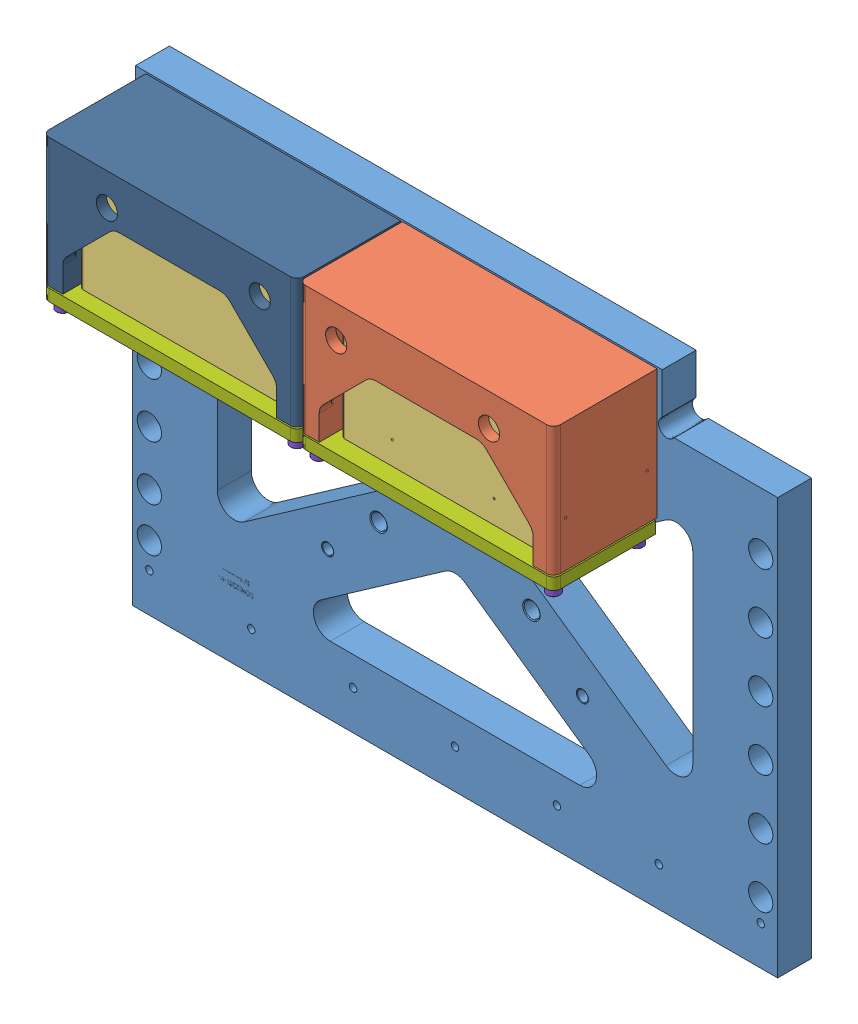
SolidWorks assembly D1001760 - Stage 1 Vibration Absorber (door), configuration Default. Lengths in mm.
Overall size (482.6 350.77 103.82).
71 component instances, 11 part files, 155 mates.
Components (placement in the parent):
- D0902281 Door, Stage 1, BSC ISI-1: D0902281 Door, Stage 1, BSC ISI [1-Inch Stretch] at origin size (482.6 350.77 25.4)
- D1001759 - Left clamp for Stage 1 Vibration Absorber-1: D1001759 - Left clamp for Stage 1 Vibration Absorber [Default] at (55.88 125.857 25.4) x (-1 0 0) z (0 1 0) size (190.5 77.47 96.52)
- D1001758 - Mass for Stage 1 Vibration Absorber-1: D1001758 - Mass for Stage 1 Vibration Absorber [Default] at (57.15 120.2373 35.56) x (1 0 0) z (0 -1 0) size (152.4 55.88 84.61)
- D1000939 Viton for SEI vibration absorbers with 10% strain-9: D1000939 Viton for SEI vibration absorbers with 10% strain [Default] at (126.492 162.5409 42.418) size (3.56 1.42 3.56)
- D1000939 Viton for SEI vibration absorbers with 10% strain-10: D1000939 Viton for SEI vibration absorbers with 10% strain [Default] at (-14.732 162.5409 42.418) size (3.56 1.42 3.56)
- D1000939 Viton for SEI vibration absorbers with 10% strain-11: D1000939 Viton for SEI vibration absorbers with 10% strain [Default] at (126.492 162.5409 85.852) size (3.56 1.42 3.56)
- D1000939 Viton for SEI vibration absorbers with 10% strain-12: D1000939 Viton for SEI vibration absorbers with 10% strain [Default] at (-14.732 162.5409 85.852) size (3.56 1.42 3.56)
- D1000939 Viton for SEI vibration absorbers with 10% strain-13: D1000939 Viton for SEI vibration absorbers with 10% strain [Default] at (126.492 76.5175 42.418) size (3.56 1.42 3.56)
- D1000939 Viton for SEI vibration absorbers with 10% strain-14: D1000939 Viton for SEI vibration absorbers with 10% strain [Default] at (-14.732 76.5175 42.418) size (3.56 1.42 3.56)
- D1000939 Viton for SEI vibration absorbers with 10% strain-15: D1000939 Viton for SEI vibration absorbers with 10% strain [Default] at (-14.732 76.5175 85.852) size (3.56 1.42 3.56)
- D1000939 Viton for SEI vibration absorbers with 10% strain-16: D1000939 Viton for SEI vibration absorbers with 10% strain [Default] at (126.492 76.5175 85.852) size (3.56 1.42 3.56)
- MC MASTER_93574A513-1: MC MASTER_93574A513 [Default] at (143.51 77.089 95.25) size (9.47 0.51 9.47)
- MC MASTER_93574A513-2: MC MASTER_93574A513 [Default] at (143.51 76.581 95.25) size (9.47 0.51 9.47)
- MC MASTER_93574A505-1: MC MASTER_93574A505 [Default] at (143.51 76.5048 95.25) x (0.999977 0 0.00673) z (0 1 0) size (9.47 9.47 0.08)
- D1001757 - Top clamp for Stage 1 Vibration Absorber-1: D1001757 - Top clamp for Stage 1 Vibration Absorber [Default] at (55.88 67.6148 64.77) size (190.5 8.89 76.2)
- MC MASTER_93574A513-3: MC MASTER_93574A513 [Default] at (-31.75 77.089 95.25) x (0.993606 0 -0.112902) z (0.112902 0 0.993606) size (9.47 0.51 9.47)
- MC MASTER_93574A513-4: MC MASTER_93574A513 [Default] at (-31.75 76.581 95.25) size (9.47 0.51 9.47)
- MC MASTER_93574A505-2: MC MASTER_93574A505 [Default] at (-31.75 76.5048 95.25) x (1 0 0) z (0 1 0) size (9.47 9.47 0.08)
- MC MASTER_93574A513-5: MC MASTER_93574A513 [Default] at (-31.75 77.089 33.02) size (9.47 0.51 9.47)
- MC MASTER_93574A513-6: MC MASTER_93574A513 [Default] at (-31.75 76.581 33.02) size (9.47 0.51 9.47)
- MC MASTER_93574A505-3: MC MASTER_93574A505 [Default] at (-31.75 76.5048 33.02) x (0.59125 0 -0.806489) z (0 1 0) size (9.47 9.47 0.08)
- MC MASTER_93574A513-7: MC MASTER_93574A513 [Default] at (143.51 77.089 33.02) x (0.880275 0 -0.474465) z (0.474465 0 0.880275) size (9.47 0.51 9.47)
- MC MASTER_93574A513-8: MC MASTER_93574A513 [Default] at (143.51 76.581 33.02) x (0.988184 0 -0.153269) z (0.153269 0 0.988184) size (9.47 0.51 9.47)
- MC MASTER_93574A505-4: MC MASTER_93574A505 [Default] at (143.51 76.5048 33.02) x (0.954256 0 -0.298991) z (0 1 0) size (9.47 9.47 0.08)
- HOLOKROME_78062-1: HOLOKROME_78062 [.250-20 x 1.0L] at (143.51 67.1068 95.25) x (-0.982351 0 0.187046) z (0.187046 0 0.982351) size (9.53 31.75 9.53)
- MC MASTER 96861A600-1: MC MASTER 96861A600 [96861A600] at (143.51 67.3608 95.25) x (0.307511 0 0.951544) z (0 1 0) size (11.94 11.94 0.52)
- HOLOKROME_78062-3: HOLOKROME_78062 [.250-20 x 1.0L] at (143.51 67.1068 33.02) x (-0.709304 0 0.704903) z (0.704903 0 0.709304) size (9.53 31.75 9.53)
- HOLOKROME_78062-5: HOLOKROME_78062 [.250-20 x 1.0L] at (-31.75 67.1068 33.02) x (0.117481 0 0.993075) z (0.993075 0 -0.117481) size (9.53 31.75 9.53)
- HOLOKROME_78062-4: HOLOKROME_78062 [.250-20 x 1.0L] at (-31.75 67.1068 95.25) x (-0.122585 0 0.992458) z (0.992458 0 0.122585) size (9.53 31.75 9.53)
- D1001764 Right clamp for Stage 1 Vibration Absorber-1: D1001764 Right clamp for Stage 1 Vibration Absorber [Default] at (-135.89 125.857 25.4) x (-1 0 0) z (0 1 0) size (190.5 77.47 96.52)
- D1001758 - Mass for Stage 1 Vibration Absorber-2: D1001758 - Mass for Stage 1 Vibration Absorber [Default] at (-137.3357 120.2373 92.71) x (-1 0 0) z (0 -1 0) size (152.4 55.88 84.61)
- D1000939 Viton for SEI vibration absorbers with 10% strain-17: D1000939 Viton for SEI vibration absorbers with 10% strain [Default] at (-65.278 163.957 42.418) x (-1 0 0) z (0 0 1) size (3.56 1.42 3.56)
- D1000939 Viton for SEI vibration absorbers with 10% strain-18: D1000939 Viton for SEI vibration absorbers with 10% strain [Default] at (-206.502 162.5409 42.418) size (3.56 1.42 3.56)
- D1000939 Viton for SEI vibration absorbers with 10% strain-19: D1000939 Viton for SEI vibration absorbers with 10% strain [Default] at (-206.502 162.5409 89.408) x (-1 0 0) z (0 0 -1) size (3.56 1.42 3.56)
- D1000939 Viton for SEI vibration absorbers with 10% strain-20: D1000939 Viton for SEI vibration absorbers with 10% strain [Default] at (-65.278 162.5409 85.852) size (3.56 1.42 3.56)
- D1000939 Viton for SEI vibration absorbers with 10% strain-21: D1000939 Viton for SEI vibration absorbers with 10% strain [Default] at (-65.278 76.5175 85.852) size (3.56 1.42 3.56)
- D1000939 Viton for SEI vibration absorbers with 10% strain-22: D1000939 Viton for SEI vibration absorbers with 10% strain [Default] at (-65.278 76.5175 42.418) size (3.56 1.42 3.56)
- D1000939 Viton for SEI vibration absorbers with 10% strain-23: D1000939 Viton for SEI vibration absorbers with 10% strain [Default] at (-206.502 76.5175 42.418) size (3.56 1.42 3.56)
- D1000939 Viton for SEI vibration absorbers with 10% strain-24: D1000939 Viton for SEI vibration absorbers with 10% strain [Default] at (-206.502 76.5175 85.852) size (3.56 1.42 3.56)
- D1001757 - Top clamp for Stage 1 Vibration Absorber-2: D1001757 - Top clamp for Stage 1 Vibration Absorber [Default] at (-135.89 67.6148 64.77) size (190.5 8.89 76.2)
- MC MASTER_93574A513-9: MC MASTER_93574A513 [Default] at (-48.26 77.089 95.25) size (9.47 0.51 9.47)
- MC MASTER_93574A513-10: MC MASTER_93574A513 [Default] at (-48.26 76.581 95.25) size (9.47 0.51 9.47)
- MC MASTER_93574A505-5: MC MASTER_93574A505 [Default] at (-48.26 76.5048 95.25) x (1 0 0) z (0 1 0) size (9.47 9.47 0.08)
- MC MASTER_93574A513-11: MC MASTER_93574A513 [Default] at (-48.26 77.089 33.02) size (9.47 0.51 9.47)
- MC MASTER_93574A513-12: MC MASTER_93574A513 [Default] at (-48.26 76.581 33.02) size (9.47 0.51 9.47)
- MC MASTER_93574A505-6: MC MASTER_93574A505 [Default] at (-48.26 76.5048 33.02) x (1 0 0) z (0 1 0) size (9.47 9.47 0.08)
- MC MASTER_93574A513-13: MC MASTER_93574A513 [Default] at (-223.52 77.089 33.02) size (9.47 0.51 9.47)
- MC MASTER_93574A513-14: MC MASTER_93574A513 [Default] at (-223.52 76.581 33.02) size (9.47 0.51 9.47)
- MC MASTER_93574A505-7: MC MASTER_93574A505 [Default] at (-223.52 76.5048 33.02) x (1 0 0) z (0 1 0) size (9.47 9.47 0.08)
- MC MASTER_93574A513-15: MC MASTER_93574A513 [Default] at (-223.52 77.089 95.25) size (9.47 0.51 9.47)
- MC MASTER_93574A513-16: MC MASTER_93574A513 [Default] at (-223.52 76.581 95.25) size (9.47 0.51 9.47)
- MC MASTER_93574A505-8: MC MASTER_93574A505 [Default] at (-223.52 76.5048 95.25) x (1 0 0) z (0 1 0) size (9.47 9.47 0.08)
- MC MASTER 96861A600-5: MC MASTER 96861A600 [96861A600] at (-48.26 67.3608 95.25) x (1 0 0) z (0 1 0) size (11.94 11.94 0.52)
- HOLOKROME_78062-6: HOLOKROME_78062 [.250-20 x 1.0L] at (-48.26 67.1068 95.25) x (0.448283 0 -0.893892) z (-0.893892 0 -0.448283) size (9.53 31.75 9.53)
- HOLOKROME_78062-9: HOLOKROME_78062 [.250-20 x 1.0L] at (-223.52 67.1068 95.25) x (-0.362071 0 -0.93215) z (-0.93215 0 0.362071) size (9.53 31.75 9.53)
- HOLOKROME_78062-10: HOLOKROME_78062 [.250-20 x 1.0L] at (-223.52 67.1068 33.02) x (0.443089 0 -0.896478) z (-0.896478 0 -0.443089) size (9.53 31.75 9.53)
- HOLOKROME_78062-8: HOLOKROME_78062 [.250-20 x 1.0L] at (-48.26 67.1068 33.02) x (0.795854 0 -0.605488) z (-0.605488 0 -0.795854) size (9.53 31.75 9.53)
- MSC 48632822-1: MSC 48632822 [93615A520] at (102.87 97.917 2.54) x (-0.923728 -0.383049 0) z (0 0 -1) size (14.27 14.27 31.94)
- MSC 48632822-5: MSC 48632822 [93615A520] at (-11.43 97.917 2.54) x (-0.923728 -0.383049 0) z (0 0 -1) size (14.27 14.27 31.94)
- MSC 48632822-6: MSC 48632822 [93615A520] at (102.87 149.987 2.54) x (-0.923728 -0.383049 0) z (0 0 -1) size (14.27 14.27 31.94)
- MSC 48632822-7: MSC 48632822 [93615A520] at (-11.43 149.987 2.54) x (-0.923728 -0.383049 0) z (0 0 -1) size (14.27 14.27 31.94)
- MSC 48632822-8: MSC 48632822 [93615A520] at (-182.88 97.917 2.54) x (-0.923728 -0.383049 0) z (0 0 -1) size (14.27 14.27 31.94)
- MSC 48632822-10: MSC 48632822 [93615A520] at (-182.88 149.987 2.54) x (-0.923728 -0.383049 0) z (0 0 -1) size (14.27 14.27 31.94)
- MSC 48632822-11: MSC 48632822 [93615A520] at (-68.58 97.917 2.54) x (-0.923728 -0.383049 0) z (0 0 -1) size (14.27 14.27 31.94)
- MSC 48632822-12: MSC 48632822 [93615A520] at (-68.58 149.987 2.54) x (-0.923728 -0.383049 0) z (0 0 -1) size (14.27 14.27 31.94)
- MC MASTER 96861A600-2: MC MASTER 96861A600 [96861A600] at (-31.6876 67.3608 95.4288) x (-0.833011 0 -0.553256) z (0 1 0) size (11.94 11.94 0.52)
- MC MASTER 96861A600-3: MC MASTER 96861A600 [96861A600] at (-31.4805 67.3608 33.4836) x (-0.299196 0 -0.954192) z (0 1 0) size (11.94 11.94 0.52)
- MC MASTER 96861A600-4: MC MASTER 96861A600 [96861A600] at (143.1765 67.3608 33.3053) x (0.837808 0 0.545966) z (0 1 0) size (11.94 11.94 0.52)
- MC MASTER 96861A600-6: MC MASTER 96861A600 [96861A600] at (-223.4576 67.3608 95.4288) x (-0.782608 0 0.622515) z (0 1 0) size (11.94 11.94 0.52)
- MC MASTER 96861A600-7: MC MASTER 96861A600 [96861A600] at (-223.2505 67.3608 33.4836) x (-0.999962 0 -0.008727) z (0 1 0) size (11.94 11.94 0.52)
- MC MASTER 96861A600-8: MC MASTER 96861A600 [96861A600] at (-48.5935 67.3608 33.3053) x (0.777146 0 -0.62932) z (0 1 0) size (11.94 11.94 0.52)
Mates (geometry in assembly coordinates):
- Coincident1: coincident anti-aligned: plane of D0902281 Door, Stage 1, BSC ISI-1 through (-241.3 -175.387 25.4) normal (0 0 1); plane of D1001759 - Left clamp for Stage 1 Vibration Absorber-1 through (151.13 77.597 25.4) normal (0 0 -1)
- Concentric2: concentric aligned: cylinder of D0902281 Door, Stage 1, BSC ISI-1 through (-11.43 97.917 25.4) axis (0 0 1) radius 5.8445; cylinder of D1001759 - Left clamp for Stage 1 Vibration Absorber-1 through (-11.43 97.917 33.02) axis (0 0 1) radius 5.1587
- Concentric3: concentric aligned: cylinder of D0902281 Door, Stage 1, BSC ISI-1 through (102.87 149.987 25.4) axis (0 0 1) radius 5.8445; cylinder of D1001759 - Left clamp for Stage 1 Vibration Absorber-1 through (102.87 149.987 33.02) axis (0 0 1) radius 5.1587
- Distance2: distance = 2.54 mm anti-aligned: plane of D1001758 - Mass for Stage 1 Vibration Absorber-1 through (-19.05 162.5409 35.56) normal (0 0 -1); plane of D1001759 - Left clamp for Stage 1 Vibration Absorber-1 through (-24.13 163.957 33.02) normal (0 0 1)
- Distance11: distance = 2.54 mm anti-aligned: plane of D1001758 - Mass for Stage 1 Vibration Absorber-1 through (133.35 77.9336 91.44) normal (1 0 0); plane of D1001759 - Left clamp for Stage 1 Vibration Absorber-1 through (135.89 163.957 95.25) normal (-1 0 0)
- Coincident50: coincident anti-aligned: plane of D1001759 - Left clamp for Stage 1 Vibration Absorber-1 through (135.89 163.957 33.02) normal (0 -1 0); plane of D1000939 Viton for SEI vibration absorbers with 10% strain-9 through (128.27 163.957 40.64) normal (0 1 0)
- Distance20: distance = 7.62 mm anti-aligned: plane of D1000939 Viton for SEI vibration absorbers with 10% strain-9 through (124.714 163.957 40.64) normal (0 0 -1); plane of D1001759 - Left clamp for Stage 1 Vibration Absorber-1 through (-24.13 163.957 33.02) normal (0 0 1)
- Distance21: distance = 7.62 mm anti-aligned: plane of D1000939 Viton for SEI vibration absorbers with 10% strain-9 through (128.27 163.957 44.196) normal (1 0 0); plane of D1001759 - Left clamp for Stage 1 Vibration Absorber-1 through (135.89 163.957 95.25) normal (-1 0 0)
- Coincident53: coincident anti-aligned: plane of D1001759 - Left clamp for Stage 1 Vibration Absorber-1 through (135.89 163.957 33.02) normal (0 -1 0); plane of D1000939 Viton for SEI vibration absorbers with 10% strain-10 through (-12.954 163.957 40.64) normal (0 1 0)
- Distance22: distance = 7.62 mm anti-aligned: plane of D1000939 Viton for SEI vibration absorbers with 10% strain-10 through (-16.51 163.957 44.196) normal (-1 0 0); plane of D1001759 - Left clamp for Stage 1 Vibration Absorber-1 through (-24.13 163.957 95.25) normal (1 0 0)
- Distance23: distance = 7.62 mm anti-aligned: plane of D1000939 Viton for SEI vibration absorbers with 10% strain-10 through (-16.51 163.957 40.64) normal (0 0 -1); plane of D1001759 - Left clamp for Stage 1 Vibration Absorber-1 through (-24.13 163.957 33.02) normal (0 0 1)
- Coincident56: coincident anti-aligned: plane of D1001759 - Left clamp for Stage 1 Vibration Absorber-1 through (135.89 163.957 33.02) normal (0 -1 0); plane of D1000939 Viton for SEI vibration absorbers with 10% strain-11 through (128.27 163.957 84.074) normal (0 1 0)
- Distance24: distance = 7.62 mm anti-aligned: plane of D1000939 Viton for SEI vibration absorbers with 10% strain-11 through (128.27 163.957 87.63) normal (1 0 0); plane of D1001759 - Left clamp for Stage 1 Vibration Absorber-1 through (135.89 163.957 95.25) normal (-1 0 0)
- Distance25: distance = 7.62 mm anti-aligned: plane of D1000939 Viton for SEI vibration absorbers with 10% strain-11 through (124.714 163.957 87.63) normal (0 0 1); plane of D1001759 - Left clamp for Stage 1 Vibration Absorber-1 through (135.89 163.957 95.25) normal (0 0 -1)
- Coincident59: coincident anti-aligned: plane of D1001759 - Left clamp for Stage 1 Vibration Absorber-1 through (135.89 163.957 33.02) normal (0 -1 0); plane of D1000939 Viton for SEI vibration absorbers with 10% strain-12 through (-12.954 163.957 84.074) normal (0 1 0)
- Distance26: distance = 7.62 mm anti-aligned: plane of D1000939 Viton for SEI vibration absorbers with 10% strain-12 through (-16.51 163.957 87.63) normal (-1 0 0); plane of D1001759 - Left clamp for Stage 1 Vibration Absorber-1 through (-24.13 163.957 95.25) normal (1 0 0)
- Distance27: distance = 7.62 mm anti-aligned: plane of D1000939 Viton for SEI vibration absorbers with 10% strain-12 through (-16.51 163.957 87.63) normal (0 0 1); plane of D1001759 - Left clamp for Stage 1 Vibration Absorber-1 through (135.89 163.957 95.25) normal (0 0 -1)
- Coincident62: coincident anti-aligned: plane of D1001758 - Mass for Stage 1 Vibration Absorber-1 through (133.35 162.5409 91.44) normal (0 1 0); plane of D1000939 Viton for SEI vibration absorbers with 10% strain-9 through (128.27 162.5409 40.64) normal (0 -1 0)
- Coincident67: coincident anti-aligned: plane of D1001758 - Mass for Stage 1 Vibration Absorber-1 through (133.35 77.9336 91.44) normal (0 -1 0); plane of D1000939 Viton for SEI vibration absorbers with 10% strain-13 through (128.27 77.9336 40.64) normal (0 1 0)
- Distance28: distance = 7.62 mm anti-aligned: plane of D1000939 Viton for SEI vibration absorbers with 10% strain-13 through (124.714 77.9336 40.64) normal (0 0 -1); plane of D1001759 - Left clamp for Stage 1 Vibration Absorber-1 through (-24.13 163.957 33.02) normal (0 0 1)
- Distance29: distance = 7.62 mm anti-aligned: plane of D1000939 Viton for SEI vibration absorbers with 10% strain-13 through (128.27 77.9336 44.196) normal (1 0 0); plane of D1001759 - Left clamp for Stage 1 Vibration Absorber-1 through (135.89 163.957 95.25) normal (-1 0 0)
- Distance30: distance = 7.62 mm anti-aligned: plane of D1001759 - Left clamp for Stage 1 Vibration Absorber-1 through (-24.13 163.957 33.02) normal (0 0 1); plane of D1000939 Viton for SEI vibration absorbers with 10% strain-14 through (-16.51 77.9336 40.64) normal (0 0 -1)
- Distance31: distance = 7.62 mm anti-aligned: plane of D1000939 Viton for SEI vibration absorbers with 10% strain-14 through (-16.51 77.9336 44.196) normal (-1 0 0); plane of D1001759 - Left clamp for Stage 1 Vibration Absorber-1 through (-24.13 163.957 95.25) normal (1 0 0)
- Coincident72: coincident anti-aligned: plane of D1001758 - Mass for Stage 1 Vibration Absorber-1 through (133.35 77.9336 91.44) normal (0 -1 0); plane of D1000939 Viton for SEI vibration absorbers with 10% strain-14 through (-12.954 77.9336 40.64) normal (0 1 0)
- Coincident73: coincident anti-aligned: plane of D1001758 - Mass for Stage 1 Vibration Absorber-1 through (133.35 77.9336 91.44) normal (0 -1 0); plane of D1000939 Viton for SEI vibration absorbers with 10% strain-15 through (-12.954 77.9336 84.074) normal (0 1 0)
- Distance32: distance = 7.62 mm anti-aligned: plane of D1000939 Viton for SEI vibration absorbers with 10% strain-15 through (-16.51 77.9336 87.63) normal (-1 0 0); plane of D1001759 - Left clamp for Stage 1 Vibration Absorber-1 through (-24.13 163.957 95.25) normal (1 0 0)
- Distance33: distance = 7.62 mm anti-aligned: plane of D1000939 Viton for SEI vibration absorbers with 10% strain-15 through (-16.51 77.9336 87.63) normal (0 0 1); plane of D1001759 - Left clamp for Stage 1 Vibration Absorber-1 through (135.89 163.957 95.25) normal (0 0 -1)
- Coincident76: coincident anti-aligned: plane of D1001758 - Mass for Stage 1 Vibration Absorber-1 through (133.35 77.9336 91.44) normal (0 -1 0); plane of D1000939 Viton for SEI vibration absorbers with 10% strain-16 through (128.27 77.9336 84.074) normal (0 1 0)
- Distance34: distance = 7.62 mm anti-aligned: plane of D1000939 Viton for SEI vibration absorbers with 10% strain-16 through (124.714 77.9336 87.63) normal (0 0 1); plane of D1001759 - Left clamp for Stage 1 Vibration Absorber-1 through (135.89 163.957 95.25) normal (0 0 -1)
- Distance35: distance = 7.62 mm anti-aligned: plane of D1000939 Viton for SEI vibration absorbers with 10% strain-16 through (128.27 77.9336 87.63) normal (1 0 0); plane of D1001759 - Left clamp for Stage 1 Vibration Absorber-1 through (135.89 163.957 95.25) normal (-1 0 0)
- Coincident79: coincident anti-aligned: plane of D1001759 - Left clamp for Stage 1 Vibration Absorber-1 through (-39.37 77.597 102.87) normal (0 -1 0); plane of MC MASTER_93574A513-1 through (143.51 77.597 95.25) normal (0 1 0)
- Concentric16: concentric anti-aligned: cylinder of D1001759 - Left clamp for Stage 1 Vibration Absorber-1 through (143.51 77.597 95.25) axis (0 -1 0) radius 2.5527; circle of MC MASTER_93574A513-1
- Coincident80: coincident anti-aligned: plane of MC MASTER_93574A513-1 through (143.51 77.089 95.25) normal (0 -1 0); plane of MC MASTER_93574A513-2 through (143.51 77.089 95.25) normal (0 1 0)
- Concentric17: concentric anti-aligned: cylinder of D1001759 - Left clamp for Stage 1 Vibration Absorber-1 through (143.51 77.597 95.25) axis (0 -1 0) radius 2.5527; circle of MC MASTER_93574A513-2
- Coincident82: coincident anti-aligned: plane of MC MASTER_93574A513-2 through (143.51 76.581 95.25) normal (0 -1 0); plane of MC MASTER_93574A505-1 through (143.51 76.581 95.25) normal (0 1 0)
- Concentric18: concentric anti-aligned: cylinder of D1001759 - Left clamp for Stage 1 Vibration Absorber-1 through (143.51 77.597 95.25) axis (0 -1 0) radius 2.5527; circle of MC MASTER_93574A505-1
- Coincident83: coincident anti-aligned: plane of MC MASTER_93574A505-1 through (143.51 76.5048 95.25) normal (0 -1 0); plane of D1001757 - Top clamp for Stage 1 Vibration Absorber-1 through (-39.37 76.5048 26.67) normal (0 1 0)
- Coincident84: coincident anti-aligned: plane of D1001759 - Left clamp for Stage 1 Vibration Absorber-1 through (-39.37 77.597 102.87) normal (0 -1 0); plane of MC MASTER_93574A513-3 through (-31.75 77.597 95.25) normal (0 1 0)
- Concentric21: concentric anti-aligned: cylinder of D1001759 - Left clamp for Stage 1 Vibration Absorber-1 through (-31.75 77.597 95.25) axis (0 -1 0) radius 2.5527; circle of MC MASTER_93574A513-3
- Coincident85: coincident anti-aligned: plane of MC MASTER_93574A513-3 through (-31.75 77.089 95.25) normal (0 -1 0); plane of MC MASTER_93574A513-4 through (-31.75 77.089 95.25) normal (0 1 0)
- Concentric22: concentric anti-aligned: cylinder of D1001759 - Left clamp for Stage 1 Vibration Absorber-1 through (-31.75 77.597 95.25) axis (0 -1 0) radius 2.5527; circle of MC MASTER_93574A513-4
- Coincident86: coincident anti-aligned: plane of MC MASTER_93574A513-4 through (-31.75 76.581 95.25) normal (0 -1 0); plane of MC MASTER_93574A505-2 through (-31.75 76.581 95.25) normal (0 1 0)
- Concentric23: concentric anti-aligned: cylinder of D1001759 - Left clamp for Stage 1 Vibration Absorber-1 through (-31.75 77.597 95.25) axis (0 -1 0) radius 2.5527; circle of MC MASTER_93574A505-2
- Coincident87: coincident anti-aligned: plane of D1001759 - Left clamp for Stage 1 Vibration Absorber-1 through (-39.37 77.597 102.87) normal (0 -1 0); plane of MC MASTER_93574A513-5 through (-31.75 77.597 33.02) normal (0 1 0)
- Concentric24: concentric anti-aligned: cylinder of D1001759 - Left clamp for Stage 1 Vibration Absorber-1 through (-31.75 77.597 33.02) axis (0 -1 0) radius 2.5527; circle of MC MASTER_93574A513-5
- Coincident88: coincident anti-aligned: plane of MC MASTER_93574A513-5 through (-31.75 77.089 33.02) normal (0 -1 0); plane of MC MASTER_93574A513-6 through (-31.75 77.089 33.02) normal (0 1 0)
- Concentric25: concentric anti-aligned: cylinder of D1001759 - Left clamp for Stage 1 Vibration Absorber-1 through (-31.75 77.597 33.02) axis (0 -1 0) radius 2.5527; circle of MC MASTER_93574A513-6
- Coincident89: coincident anti-aligned: plane of MC MASTER_93574A513-6 through (-31.75 76.581 33.02) normal (0 -1 0); plane of MC MASTER_93574A505-3 through (-31.75 76.581 33.02) normal (0 1 0)
- Concentric26: concentric anti-aligned: cylinder of D1001759 - Left clamp for Stage 1 Vibration Absorber-1 through (-31.75 77.597 33.02) axis (0 -1 0) radius 2.5527; circle of MC MASTER_93574A505-3
- Coincident90: coincident anti-aligned: plane of D1001759 - Left clamp for Stage 1 Vibration Absorber-1 through (-39.37 77.597 102.87) normal (0 -1 0); plane of MC MASTER_93574A513-7 through (143.51 77.597 33.02) normal (0 1 0)
- Concentric27: concentric anti-aligned: cylinder of D1001759 - Left clamp for Stage 1 Vibration Absorber-1 through (143.51 77.597 33.02) axis (0 -1 0) radius 2.5527; circle of MC MASTER_93574A513-7
- Coincident91: coincident anti-aligned: plane of MC MASTER_93574A513-7 through (143.51 77.089 33.02) normal (0 -1 0); plane of MC MASTER_93574A513-8 through (143.51 77.089 33.02) normal (0 1 0)
- Concentric28: concentric anti-aligned: cylinder of D1001759 - Left clamp for Stage 1 Vibration Absorber-1 through (143.51 77.597 33.02) axis (0 -1 0) radius 2.5527; circle of MC MASTER_93574A513-8
- Coincident92: coincident anti-aligned: plane of MC MASTER_93574A513-8 through (143.51 76.581 33.02) normal (0 -1 0); plane of MC MASTER_93574A505-4 through (143.51 76.581 33.02) normal (0 1 0)
- Concentric29: concentric anti-aligned: cylinder of D1001759 - Left clamp for Stage 1 Vibration Absorber-1 through (143.51 77.597 33.02) axis (0 -1 0) radius 2.5527; circle of MC MASTER_93574A505-4
- Concentric30: concentric aligned: cylinder of D1001759 - Left clamp for Stage 1 Vibration Absorber-1 through (143.51 77.597 95.25) axis (0 -1 0) radius 2.5527; cylinder of HOLOKROME_78062-1 through (143.51 92.5068 95.25) axis (0 -1 0) radius 3.175
- Coincident102: coincident anti-aligned: plane of D0902281 Door, Stage 1, BSC ISI-1 through (-241.3 -175.387 25.4) normal (0 0 1); plane of D1001764 Right clamp for Stage 1 Vibration Absorber-1 through (-40.64 77.597 25.4) normal (0 0 -1)
- Concentric38: concentric aligned: cylinder of D0902281 Door, Stage 1, BSC ISI-1 through (-68.58 97.917 25.4) axis (0 0 1) radius 5.8445; cylinder of D1001764 Right clamp for Stage 1 Vibration Absorber-1 through (-68.58 97.917 33.02) axis (0 0 1) radius 5.1587
- Concentric39: concentric aligned: cylinder of D0902281 Door, Stage 1, BSC ISI-1 through (-182.88 149.987 25.4) axis (0 0 1) radius 5.8445; cylinder of D1001764 Right clamp for Stage 1 Vibration Absorber-1 through (-182.88 149.987 33.02) axis (0 0 1) radius 5.1587
- Coincident107: coincident anti-aligned: plane of D1001764 Right clamp for Stage 1 Vibration Absorber-1 through (-55.88 163.957 33.02) normal (0 -1 0); plane of D1000939 Viton for SEI vibration absorbers with 10% strain-17 through (-67.056 163.957 40.64) normal (0 1 0)
- Distance36: distance = 7.62 mm anti-aligned: plane of D1000939 Viton for SEI vibration absorbers with 10% strain-17 through (-63.5 162.5409 44.196) normal (1 0 0); plane of D1001764 Right clamp for Stage 1 Vibration Absorber-1 through (-55.88 163.957 95.25) normal (-1 0 0)
- Distance37: distance = 7.62 mm anti-aligned: plane of D1000939 Viton for SEI vibration absorbers with 10% strain-17 through (-63.5 162.5409 40.64) normal (0 0 -1); plane of D1001764 Right clamp for Stage 1 Vibration Absorber-1 through (-215.9 163.957 33.02) normal (0 0 1)
- Coincident110: coincident anti-aligned: plane of D1001764 Right clamp for Stage 1 Vibration Absorber-1 through (-55.88 163.957 33.02) normal (0 -1 0); plane of D1000939 Viton for SEI vibration absorbers with 10% strain-18 through (-204.724 163.957 40.64) normal (0 1 0)
- Distance38: distance = 7.62 mm anti-aligned: plane of D1000939 Viton for SEI vibration absorbers with 10% strain-18 through (-208.28 163.957 40.64) normal (0 0 -1); plane of D1001764 Right clamp for Stage 1 Vibration Absorber-1 through (-215.9 163.957 33.02) normal (0 0 1)
- Distance39: distance = 7.62 mm anti-aligned: plane of D1000939 Viton for SEI vibration absorbers with 10% strain-18 through (-208.28 163.957 44.196) normal (-1 0 0); plane of D1001764 Right clamp for Stage 1 Vibration Absorber-1 through (-215.9 163.957 95.25) normal (1 0 0)
- Coincident113: coincident anti-aligned: plane of D1001764 Right clamp for Stage 1 Vibration Absorber-1 through (-55.88 163.957 33.02) normal (0 -1 0); plane of D1000939 Viton for SEI vibration absorbers with 10% strain-19 through (-208.28 163.957 91.186) normal (0 1 0)
- Distance40: distance = 7.62 mm aligned: plane of D1000939 Viton for SEI vibration absorbers with 10% strain-19 through (-204.724 163.957 87.63) normal (0 0 -1); plane of D1001764 Right clamp for Stage 1 Vibration Absorber-1 through (-55.88 163.957 95.25) normal (0 0 -1)
- Distance41: distance = 7.62 mm anti-aligned: plane of D1000939 Viton for SEI vibration absorbers with 10% strain-19 through (-208.28 163.957 87.63) normal (-1 0 0); plane of D1001764 Right clamp for Stage 1 Vibration Absorber-1 through (-215.9 163.957 95.25) normal (1 0 0)
- Coincident116: coincident anti-aligned: plane of D1001764 Right clamp for Stage 1 Vibration Absorber-1 through (-55.88 163.957 33.02) normal (0 -1 0); plane of D1000939 Viton for SEI vibration absorbers with 10% strain-20 through (-63.5 163.957 84.074) normal (0 1 0)
- Distance42: distance = 7.62 mm anti-aligned: plane of D1000939 Viton for SEI vibration absorbers with 10% strain-20 through (-67.056 163.957 87.63) normal (0 0 1); plane of D1001764 Right clamp for Stage 1 Vibration Absorber-1 through (-55.88 163.957 95.25) normal (0 0 -1)
- Distance43: distance = 7.62 mm anti-aligned: plane of D1000939 Viton for SEI vibration absorbers with 10% strain-20 through (-63.5 163.957 87.63) normal (1 0 0); plane of D1001764 Right clamp for Stage 1 Vibration Absorber-1 through (-55.88 163.957 95.25) normal (-1 0 0)
- Distance44: distance = 7.62 mm anti-aligned: plane of D1000939 Viton for SEI vibration absorbers with 10% strain-21 through (-63.5 77.9336 87.63) normal (1 0 0); plane of D1001764 Right clamp for Stage 1 Vibration Absorber-1 through (-55.88 163.957 95.25) normal (-1 0 0)
- Distance45: distance = 7.62 mm: plane of D1000939 Viton for SEI vibration absorbers with 10% strain-21 through (-67.056 77.9336 87.63) normal (0 0 1); line of D1001764 Right clamp for Stage 1 Vibration Absorber-1 through (-98.1884 138.557 95.25) axis (-1 0 0)
- Distance46: distance = 7.62 mm: plane of D1000939 Viton for SEI vibration absorbers with 10% strain-22 through (-63.5 77.9336 44.196) normal (1 0 0); line of D1001764 Right clamp for Stage 1 Vibration Absorber-1 through (-55.88 77.597 35.56) axis (0 0 1)
- Distance47: distance = 7.62 mm anti-aligned: plane of D1000939 Viton for SEI vibration absorbers with 10% strain-22 through (-67.056 77.9336 40.64) normal (0 0 -1); plane of D1001764 Right clamp for Stage 1 Vibration Absorber-1 through (-215.9 163.957 33.02) normal (0 0 1)
- Distance48: distance = 7.62 mm anti-aligned: plane of D1000939 Viton for SEI vibration absorbers with 10% strain-23 through (-208.28 77.9336 40.64) normal (0 0 -1); plane of D1001764 Right clamp for Stage 1 Vibration Absorber-1 through (-215.9 163.957 33.02) normal (0 0 1)
- Distance49: distance = 7.62 mm anti-aligned: plane of D1000939 Viton for SEI vibration absorbers with 10% strain-23 through (-208.28 77.9336 44.196) normal (-1 0 0); plane of D1001764 Right clamp for Stage 1 Vibration Absorber-1 through (-215.9 163.957 95.25) normal (1 0 0)
- Distance50: distance = 7.62 mm anti-aligned: plane of D1000939 Viton for SEI vibration absorbers with 10% strain-24 through (-208.28 77.9336 87.63) normal (-1 0 0); plane of D1001764 Right clamp for Stage 1 Vibration Absorber-1 through (-215.9 163.957 95.25) normal (1 0 0)
- Distance51: distance = 7.62 mm anti-aligned: plane of D1000939 Viton for SEI vibration absorbers with 10% strain-24 through (-208.28 77.9336 87.63) normal (0 0 1); plane of D1001764 Right clamp for Stage 1 Vibration Absorber-1 through (-55.88 163.957 95.25) normal (0 0 -1)
- Coincident132: coincident anti-aligned: plane of D1001758 - Mass for Stage 1 Vibration Absorber-2 through (-213.5357 162.5409 36.83) normal (0 1 0); plane of D1000939 Viton for SEI vibration absorbers with 10% strain-17 through (-67.056 162.5409 40.64) normal (0 -1 0)
- Parallel1: parallel anti-aligned: plane of D1001764 Right clamp for Stage 1 Vibration Absorber-1 through (-215.9 163.957 33.02) normal (0 0 1); plane of D1001758 - Mass for Stage 1 Vibration Absorber-2 through (-61.1357 162.5409 36.83) normal (0 0 -1)
- Coincident134: coincident anti-aligned: plane of D1001758 - Mass for Stage 1 Vibration Absorber-2 through (-213.5357 77.9336 36.83) normal (0 -1 0); plane of D1000939 Viton for SEI vibration absorbers with 10% strain-21 through (-63.5 77.9336 84.074) normal (0 1 0)
- Coincident135: coincident anti-aligned: plane of D1001758 - Mass for Stage 1 Vibration Absorber-2 through (-213.5357 77.9336 36.83) normal (0 -1 0); plane of D1000939 Viton for SEI vibration absorbers with 10% strain-22 through (-63.5 77.9336 40.64) normal (0 1 0)
- Coincident136: coincident anti-aligned: plane of D1001758 - Mass for Stage 1 Vibration Absorber-2 through (-213.5357 77.9336 36.83) normal (0 -1 0); plane of D1000939 Viton for SEI vibration absorbers with 10% strain-24 through (-204.724 77.9336 84.074) normal (0 1 0)
- Coincident137: coincident anti-aligned: plane of D1001758 - Mass for Stage 1 Vibration Absorber-2 through (-213.5357 77.9336 36.83) normal (0 -1 0); plane of D1000939 Viton for SEI vibration absorbers with 10% strain-23 through (-204.724 77.9336 40.64) normal (0 1 0)
- Distance52: distance = 2.54 mm anti-aligned: plane of D1001758 - Mass for Stage 1 Vibration Absorber-2 through (-61.1357 162.5409 92.71) normal (0 0 1); plane of D1001764 Right clamp for Stage 1 Vibration Absorber-1 through (-55.88 163.957 95.25) normal (0 0 -1)
- Distance53: distance = 5.2557 mm anti-aligned: plane of D1001764 Right clamp for Stage 1 Vibration Absorber-1 through (-55.88 163.957 95.25) normal (-1 0 0); plane of D1001758 - Mass for Stage 1 Vibration Absorber-2 through (-61.1357 77.9336 36.83) normal (1 0 0)
- Coincident141: coincident anti-aligned: plane of D1001764 Right clamp for Stage 1 Vibration Absorber-1 through (-231.14 77.597 102.87) normal (0 -1 0); plane of MC MASTER_93574A513-9 through (-48.26 77.597 95.25) normal (0 1 0)
- Concentric50: concentric anti-aligned: cylinder of D1001764 Right clamp for Stage 1 Vibration Absorber-1 through (-48.26 77.597 95.25) axis (0 -1 0) radius 2.5527; circle of MC MASTER_93574A513-9
- Coincident142: coincident anti-aligned: plane of MC MASTER_93574A513-9 through (-48.26 77.089 95.25) normal (0 -1 0); plane of MC MASTER_93574A513-10 through (-48.26 77.089 95.25) normal (0 1 0)
- Concentric51: concentric anti-aligned: cylinder of D1001764 Right clamp for Stage 1 Vibration Absorber-1 through (-48.26 77.597 95.25) axis (0 -1 0) radius 2.5527; circle of MC MASTER_93574A513-10
- Coincident143: coincident anti-aligned: plane of MC MASTER_93574A513-10 through (-48.26 76.581 95.25) normal (0 -1 0); plane of MC MASTER_93574A505-5 through (-48.26 76.581 95.25) normal (0 1 0)
- Concentric52: concentric anti-aligned: cylinder of D1001764 Right clamp for Stage 1 Vibration Absorber-1 through (-48.26 77.597 95.25) axis (0 -1 0) radius 2.5527; circle of MC MASTER_93574A505-5
- Coincident144: coincident anti-aligned: plane of D1001764 Right clamp for Stage 1 Vibration Absorber-1 through (-231.14 77.597 102.87) normal (0 -1 0); plane of MC MASTER_93574A513-11 through (-48.26 77.597 33.02) normal (0 1 0)
- Concentric53: concentric anti-aligned: cylinder of D1001764 Right clamp for Stage 1 Vibration Absorber-1 through (-48.26 77.597 33.02) axis (0 -1 0) radius 2.5527; circle of MC MASTER_93574A513-11
- Coincident145: coincident anti-aligned: plane of MC MASTER_93574A513-11 through (-48.26 77.089 33.02) normal (0 -1 0); plane of MC MASTER_93574A513-12 through (-48.26 77.089 33.02) normal (0 1 0)
- Concentric54: concentric anti-aligned: cylinder of D1001764 Right clamp for Stage 1 Vibration Absorber-1 through (-48.26 77.597 33.02) axis (0 -1 0) radius 2.5527; circle of MC MASTER_93574A513-12
- Coincident146: coincident anti-aligned: plane of MC MASTER_93574A513-12 through (-48.26 76.581 33.02) normal (0 -1 0); plane of MC MASTER_93574A505-6 through (-48.26 76.581 33.02) normal (0 1 0)
- Concentric55: concentric anti-aligned: cylinder of D1001764 Right clamp for Stage 1 Vibration Absorber-1 through (-48.26 77.597 33.02) axis (0 -1 0) radius 2.5527; circle of MC MASTER_93574A505-6
- Coincident147: coincident anti-aligned: plane of D1001764 Right clamp for Stage 1 Vibration Absorber-1 through (-231.14 77.597 102.87) normal (0 -1 0); plane of MC MASTER_93574A513-13 through (-223.52 77.597 33.02) normal (0 1 0)
- Concentric56: concentric anti-aligned: cylinder of D1001764 Right clamp for Stage 1 Vibration Absorber-1 through (-223.52 77.597 33.02) axis (0 -1 0) radius 2.5527; circle of MC MASTER_93574A513-13
- Coincident148: coincident anti-aligned: plane of MC MASTER_93574A513-13 through (-223.52 77.089 33.02) normal (0 -1 0); plane of MC MASTER_93574A513-14 through (-223.52 77.089 33.02) normal (0 1 0)
- Concentric57: concentric anti-aligned: cylinder of D1001764 Right clamp for Stage 1 Vibration Absorber-1 through (-223.52 77.597 33.02) axis (0 -1 0) radius 2.5527; circle of MC MASTER_93574A513-14
- Coincident149: coincident anti-aligned: plane of MC MASTER_93574A513-14 through (-223.52 76.581 33.02) normal (0 -1 0); plane of MC MASTER_93574A505-7 through (-223.52 76.581 33.02) normal (0 1 0)
- Concentric58: concentric anti-aligned: cylinder of D1001764 Right clamp for Stage 1 Vibration Absorber-1 through (-223.52 77.597 33.02) axis (0 -1 0) radius 2.5527; circle of MC MASTER_93574A505-7
- Coincident150: coincident anti-aligned: plane of D1001764 Right clamp for Stage 1 Vibration Absorber-1 through (-231.14 77.597 102.87) normal (0 -1 0); plane of MC MASTER_93574A513-15 through (-223.52 77.597 95.25) normal (0 1 0)
- Concentric59: concentric anti-aligned: cylinder of D1001764 Right clamp for Stage 1 Vibration Absorber-1 through (-223.52 77.597 95.25) axis (0 -1 0) radius 2.5527; circle of MC MASTER_93574A513-15
- Coincident151: coincident anti-aligned: plane of MC MASTER_93574A513-15 through (-223.52 77.089 95.25) normal (0 -1 0); plane of MC MASTER_93574A513-16 through (-223.52 77.089 95.25) normal (0 1 0)
- Concentric60: concentric anti-aligned: cylinder of D1001764 Right clamp for Stage 1 Vibration Absorber-1 through (-223.52 77.597 95.25) axis (0 -1 0) radius 2.5527; circle of MC MASTER_93574A513-16
- Coincident152: coincident anti-aligned: plane of MC MASTER_93574A513-16 through (-223.52 76.581 95.25) normal (0 -1 0); plane of MC MASTER_93574A505-8 through (-223.52 76.581 95.25) normal (0 1 0)
- Concentric61: concentric anti-aligned: cylinder of D1001764 Right clamp for Stage 1 Vibration Absorber-1 through (-223.52 77.597 95.25) axis (0 -1 0) radius 2.5527; circle of MC MASTER_93574A505-8
- Coincident153: coincident anti-aligned: plane of D1001757 - Top clamp for Stage 1 Vibration Absorber-2 through (-231.14 76.5048 26.67) normal (0 1 0); plane of MC MASTER_93574A505-8 through (-223.52 76.5048 95.25) normal (0 -1 0)
- Concentric73: concentric anti-aligned: cylinder of D0902281 Door, Stage 1, BSC ISI-1 through (102.87 97.917 25.4) axis (0 0 1) radius 5.8445; cylinder of MSC 48632822-1 through (102.87 97.917 27.94) axis (0 0 -1) radius 4.7625
- Coincident163: coincident anti-aligned: plane of D1001759 - Left clamp for Stage 1 Vibration Absorber-1 through (97.0763 97.917 27.94) normal (0 0 1); plane of MSC 48632822-1 through (102.87 97.917 27.94) normal (0 0 -1)
- Concentric74: concentric anti-aligned: cylinder of D0902281 Door, Stage 1, BSC ISI-1 through (-11.43 97.917 25.4) axis (0 0 1) radius 5.8445; cylinder of MSC 48632822-5 through (-11.43 97.917 27.94) axis (0 0 -1) radius 4.7625
- Coincident164: coincident anti-aligned: plane of D1001759 - Left clamp for Stage 1 Vibration Absorber-1 through (-17.2237 97.917 27.94) normal (0 0 1); plane of MSC 48632822-5 through (-11.43 97.917 27.94) normal (0 0 -1)
- Concentric75: concentric anti-aligned: cylinder of D0902281 Door, Stage 1, BSC ISI-1 through (102.87 149.987 25.4) axis (0 0 1) radius 5.8445; cylinder of MSC 48632822-6 through (102.87 149.987 27.94) axis (0 0 -1) radius 4.7625
- Coincident165: coincident anti-aligned: plane of D1001759 - Left clamp for Stage 1 Vibration Absorber-1 through (97.0763 149.987 27.94) normal (0 0 1); plane of MSC 48632822-6 through (102.87 149.987 27.94) normal (0 0 -1)
- Concentric76: concentric anti-aligned: cylinder of D0902281 Door, Stage 1, BSC ISI-1 through (-11.43 149.987 25.4) axis (0 0 1) radius 5.8445; cylinder of MSC 48632822-7 through (-11.43 149.987 27.94) axis (0 0 -1) radius 4.7625
- Coincident166: coincident anti-aligned: plane of D1001759 - Left clamp for Stage 1 Vibration Absorber-1 through (-17.2237 149.987 27.94) normal (0 0 1); plane of MSC 48632822-7 through (-11.43 149.987 27.94) normal (0 0 -1)
- Concentric78: concentric anti-aligned: cylinder of D0902281 Door, Stage 1, BSC ISI-1 through (-182.88 97.917 25.4) axis (0 0 1) radius 5.8445; cylinder of MSC 48632822-8 through (-182.88 97.917 27.94) axis (0 0 -1) radius 4.7625
- Concentric79: concentric anti-aligned: cylinder of D0902281 Door, Stage 1, BSC ISI-1 through (-182.88 149.987 25.4) axis (0 0 1) radius 5.8445; cylinder of MSC 48632822-10 through (-182.88 149.987 27.94) axis (0 0 -1) radius 4.7625
- Concentric80: concentric anti-aligned: cylinder of D0902281 Door, Stage 1, BSC ISI-1 through (-68.58 97.917 25.4) axis (0 0 1) radius 5.8445; cylinder of MSC 48632822-11 through (-68.58 97.917 27.94) axis (0 0 -1) radius 4.7625
- Concentric81: concentric anti-aligned: cylinder of D0902281 Door, Stage 1, BSC ISI-1 through (-68.58 149.987 25.4) axis (0 0 1) radius 5.8445; cylinder of MSC 48632822-12 through (-68.58 149.987 27.94) axis (0 0 -1) radius 4.7625
- Coincident167: coincident anti-aligned: plane of D1001764 Right clamp for Stage 1 Vibration Absorber-1 through (-188.6737 97.917 27.94) normal (0 0 1); plane of MSC 48632822-8 through (-182.88 97.917 27.94) normal (0 0 -1)
- Coincident168: coincident anti-aligned: plane of D1001764 Right clamp for Stage 1 Vibration Absorber-1 through (-188.6737 149.987 27.94) normal (0 0 1); plane of MSC 48632822-10 through (-182.88 149.987 27.94) normal (0 0 -1)
- Coincident169: coincident anti-aligned: plane of D1001764 Right clamp for Stage 1 Vibration Absorber-1 through (-74.3737 97.917 27.94) normal (0 0 1); plane of MSC 48632822-11 through (-68.58 97.917 27.94) normal (0 0 -1)
- Coincident170: coincident anti-aligned: plane of D1001764 Right clamp for Stage 1 Vibration Absorber-1 through (-74.3737 149.987 27.94) normal (0 0 1); plane of MSC 48632822-12 through (-68.58 149.987 27.94) normal (0 0 -1)
- Concentric85: concentric aligned: cylinder of D1001759 - Left clamp for Stage 1 Vibration Absorber-1 through (143.51 77.597 33.02) axis (0 -1 0) radius 2.5527; cylinder of HOLOKROME_78062-3 through (143.51 92.5068 33.02) axis (0 -1 0) radius 3.175
- Concentric87: concentric anti-aligned: circle of MC MASTER_93574A505-1; cylinder of HOLOKROME_78062-1 through (143.51 92.5068 95.25) axis (0 -1 0) radius 3.175
- Concentric88: concentric anti-aligned: circle of MC MASTER_93574A513-2; cylinder of HOLOKROME_78062-1 through (143.51 92.5068 95.25) axis (0 -1 0) radius 3.175
- Concentric91: concentric anti-aligned: circle of MC MASTER_93574A505-4; cylinder of HOLOKROME_78062-3 through (143.51 92.5068 33.02) axis (0 -1 0) radius 3.175
- Concentric92: concentric anti-aligned: circle of MC MASTER_93574A513-8; cylinder of HOLOKROME_78062-3 through (143.51 92.5068 33.02) axis (0 -1 0) radius 3.175
- Concentric94: concentric anti-aligned: circle of MC MASTER_93574A505-3; cylinder of HOLOKROME_78062-5 through (-31.75 92.5068 33.02) axis (0 -1 0) radius 3.175
- Concentric95: concentric aligned: cylinder of MC MASTER_93574A513-6 through (-31.75 77.089 33.02) axis (0 -1 0) radius 4.7371; cylinder of HOLOKROME_78062-5 through (-31.75 92.5068 33.02) axis (0 -1 0) radius 3.175
- Concentric96: concentric aligned: cylinder of MC MASTER_93574A513-5 through (-31.75 77.597 33.02) axis (0 -1 0) radius 4.7371; cylinder of HOLOKROME_78062-5 through (-31.75 92.5068 33.02) axis (0 -1 0) radius 3.175
- Concentric98: concentric aligned: cylinder of MC MASTER_93574A505-2 through (-31.75 76.581 95.25) axis (0 -1 0) radius 4.7371; cylinder of HOLOKROME_78062-4 through (-31.75 92.5068 95.25) axis (0 -1 0) radius 3.175
- Concentric99: concentric anti-aligned: cylinder of D1001757 - Top clamp for Stage 1 Vibration Absorber-1 through (143.51 76.5048 95.25) axis (0 1 0) radius 3.5712; cylinder of HOLOKROME_78062-1 through (143.51 92.5068 95.25) axis (0 -1 0) radius 3.175
- Concentric100: concentric anti-aligned: cylinder of D1001757 - Top clamp for Stage 1 Vibration Absorber-1 through (-31.75 76.5048 33.02) axis (0 1 0) radius 3.5712; cylinder of HOLOKROME_78062-5 through (-31.75 92.5068 33.02) axis (0 -1 0) radius 3.175
- Concentric102: concentric aligned: cylinder of MC MASTER_93574A505-8 through (-223.52 76.581 95.25) axis (0 -1 0) radius 4.7371; cylinder of HOLOKROME_78062-9 through (-223.52 92.5068 95.25) axis (0 -1 0) radius 3.175
- Concentric104: concentric aligned: cylinder of MC MASTER_93574A505-7 through (-223.52 76.581 33.02) axis (0 -1 0) radius 4.7371; cylinder of HOLOKROME_78062-10 through (-223.52 92.5068 33.02) axis (0 -1 0) radius 3.175
- Concentric106: concentric aligned: cylinder of MC MASTER_93574A505-6 through (-48.26 76.581 33.02) axis (0 -1 0) radius 4.7371; cylinder of HOLOKROME_78062-8 through (-48.26 92.5068 33.02) axis (0 -1 0) radius 3.175
- Concentric108: concentric aligned: cylinder of MC MASTER_93574A505-5 through (-48.26 76.581 95.25) axis (0 -1 0) radius 4.7371; cylinder of HOLOKROME_78062-6 through (-48.26 92.5068 95.25) axis (0 -1 0) radius 3.175
- Concentric109: concentric anti-aligned: cylinder of D1001757 - Top clamp for Stage 1 Vibration Absorber-2 through (-223.52 76.5048 95.25) axis (0 1 0) radius 3.5712; cylinder of HOLOKROME_78062-9 through (-223.52 92.5068 95.25) axis (0 -1 0) radius 3.175
- Concentric110: concentric anti-aligned: cylinder of D1001757 - Top clamp for Stage 1 Vibration Absorber-2 through (-48.26 76.5048 33.02) axis (0 1 0) radius 3.5712; cylinder of HOLOKROME_78062-8 through (-48.26 92.5068 33.02) axis (0 -1 0) radius 3.175
- Coincident171: coincident anti-aligned: plane of D1001757 - Top clamp for Stage 1 Vibration Absorber-1 through (-39.37 67.6148 26.67) normal (0 -1 0); plane of MC MASTER 96861A600-1 through (143.51 67.6148 95.25) normal (0 1 0)
- Concentric111: concentric aligned: cylinder of HOLOKROME_78062-1 through (143.51 60.7568 95.25) axis (0 1 0) radius 4.7625; circle of MC MASTER 96861A600-1
- Coincident172: coincident anti-aligned: plane of HOLOKROME_78062-1 through (143.51 67.1068 95.25) normal (0 1 0); plane of MC MASTER 96861A600-1 through (143.51 67.1068 95.25) normal (0 -1 0)
- Coincident173: coincident anti-aligned: plane of D1001757 - Top clamp for Stage 1 Vibration Absorber-2 through (-231.14 67.6148 26.67) normal (0 -1 0); plane of MC MASTER 96861A600-5 through (-48.26 67.6148 95.25) normal (0 1 0)
- Coincident174: coincident anti-aligned: plane of MC MASTER 96861A600-5 through (-48.26 67.1068 95.25) normal (0 -1 0); plane of HOLOKROME_78062-6 through (-48.26 67.1068 95.25) normal (0 1 0)
- Concentric112: concentric anti-aligned: cylinder of MC MASTER 96861A600-5 through (-48.26 67.6148 95.25) axis (0 -1 0) radius 3.175; cylinder of HOLOKROME_78062-6 through (-48.26 60.7568 95.25) axis (0 1 0) radius 4.7625
- Point2: unknown: edge_curve of ?
- Point3: unknown: edge_curve of D1001757 - Top clamp for Stage 1 Vibration Absorber-1
- Point4: unknown: edge_curve of D1001757 - Top clamp for Stage 1 Vibration Absorber-2
- Axis2: unknown: plane of D1001757 - Top clamp for Stage 1 Vibration Absorber-2 through (-231.14 67.6148 26.67) normal (0 -1 0)
